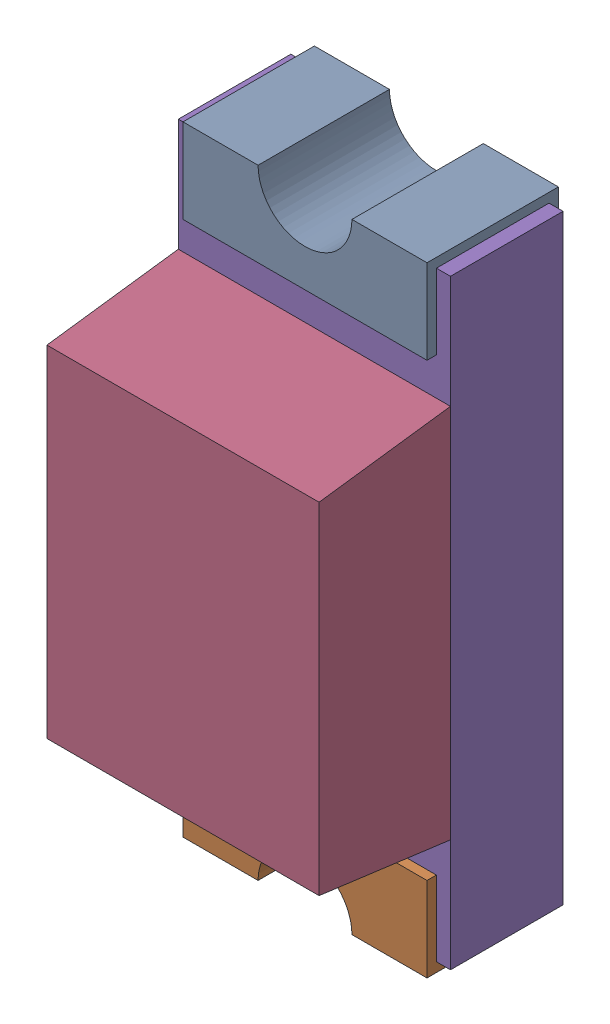
SolidWorks assembly P6, configuration Standard. Lengths in mm.
Overall size (0.73 1.65 0.68).
6 component instances, 5 part files, 0 mates.
Components (placement in the parent):
- P6-subassembly-1-1: P6-subassembly-1 [Standard] at (-15.4999 2.3499 0) x (1 0 0) z (0 0 1) size (0.72 1.65 0.68)
  - User Library-LED SMD0603-1: User Library-LED SMD0603 [Standard] at origin size (0.65 0.28 0.35)
  - User Library-LED SMD0603-1-1: User Library-LED SMD0603-1 [Standard] at origin size (0.65 0.28 0.35)
  - User Library-LED SMD0603-2-1: User Library-LED SMD0603-2 [Standard] at origin size (0.15 0.16 0.07)
  - User Library-LED SMD0603-3-1: User Library-LED SMD0603-3 [Standard] at origin size (0.72 1 0.35)
  - User Library-LED SMD0603-4-1: User Library-LED SMD0603-4 [Standard] at origin size (0.72 1.6 0.3)
